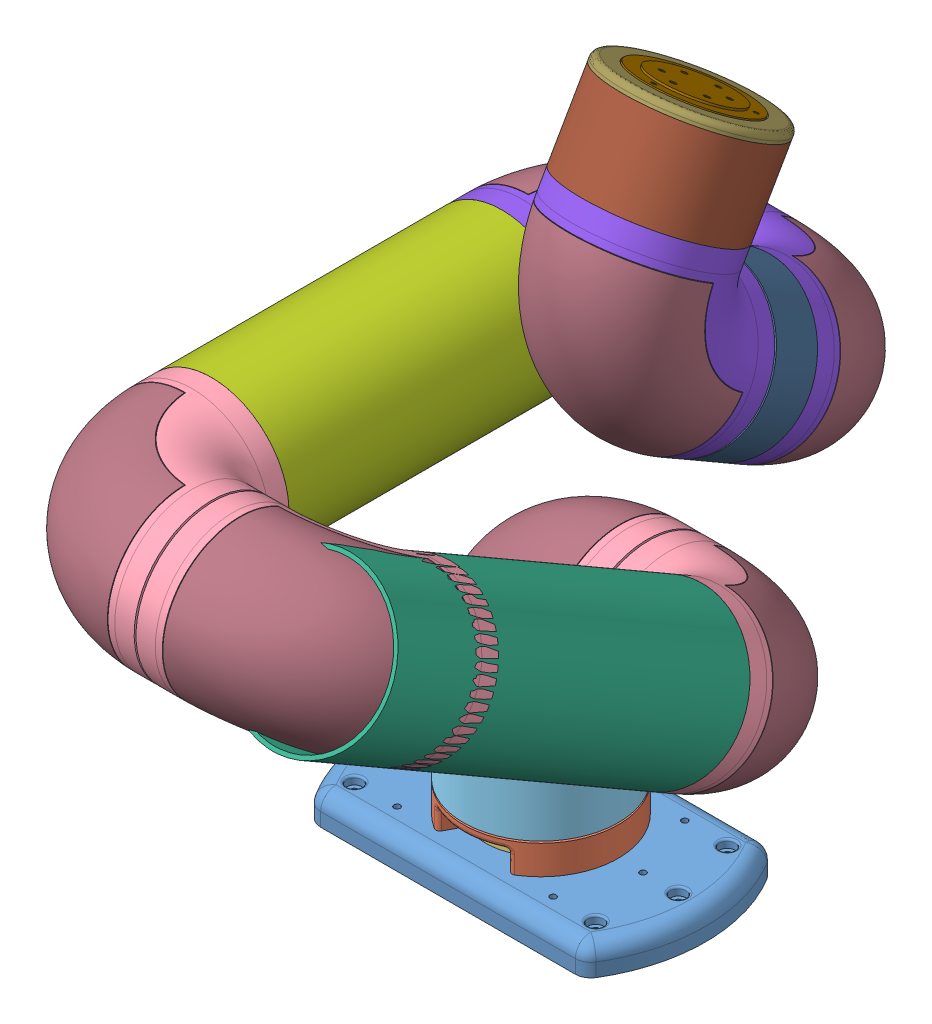
SolidWorks assembly LEG, configuration 默认. Lengths in mm.
Overall size (238.86 430.9 376.17).
28 component instances, 13 part files, 71 mates.
Components (placement in the parent):
- A1-1: A1 [默认] at (-39.3023 -20.665 170) size (170 15 96)
- A2-1: A2 [默认] at (-39.3023 9.335 170) x (0.707107 0 -0.707107) z (-0.707107 0 -0.707107) size (80 15 80)
- 4340_sim-1: 4340_sim [默认] at (-39.3023 63.585 170) x (0 0 1) z (1 0 0) size (57 53.25 57)
- B1-1: B1 [默认] at (-39.3023 49.585 170) size (96.96 109.09 84.56)
- L1-1: L1 [默认] at (-39.3023 10.285 170) size (80 39.3 80)
- 4340_sim-2: 4340_sim [默认] at (-26.4523 104.585 170) x (0 -1 0) z (0 0 1) size (57 53.25 57)
- B1-2: B1 [默认] at (71.6477 132.085 217.6314) x (-1 0 0) z (0 -0.866025 0.5) size (96.96 109.09 84.56)
- L2-1: L2 [默认] at (71.6477 132.085 217.6314) x (1 0 0) z (0 -0.866025 0.5) size (80 210 80)
- B1-3: B1 [默认] at (71.6477 207.085 347.5352) x (-1 0 0) z (0 0.866025 -0.5) size (96.96 109.09 84.56)
- 4340_sim-3: 4340_sim [默认] at (58.7977 234.585 395.1666) x (0 0.866025 -0.5) z (0 0.5 0.866025) size (57 53.25 57)
- B1-4: B1 [默认] at (-39.3023 234.585 340.1666) x (1 0 0) z (0 -1 0) size (96.96 109.09 84.56)
- L3-1: L3 [默认] at (-39.3023 234.585 190.1666) x (1 0 0) z (0 -1 0) size (80 150 80)
- B2-1: B2 [默认] at (-39.3023 234.585 190.1666) x (1 0 0) z (0 1 0) size (96.96 109.09 84.56)
- DM4310_sim-1: DM4310_sim [默认] at (-30.6059 48.3844 133.1666) x (0 0 -1) z (0.993049 -0.117702 0) size (57 61.9 51.54)
- B2-2: B2 [默认] at (71.6977 262.085 182.798) x (-1 0 0) z (0 -0.866025 0.5) size (96.96 109.09 84.56)
- L4-1: L4 [默认] at (71.6977 262.085 182.798) x (1 0 0) z (0 -0.866025 0.5) size (80 24.5 80)
- B2-3: B2 [默认] at (71.6977 349.9664 225.013) x (0 -0.5 -0.866025) z (-1 0 0) size (96.96 109.09 84.56)
- DM4310_sim-2: DM4310_sim [默认] at (73.6977 89.9288 257.0159) x (1 0 0) z (0 0.394592 0.918857) size (57 61.9 51.54)
- L6-1: L6 [默认] at (71.6977 349.9664 225.013) x (1 0 0) z (0 0.5 0.866025) size (80 42 80)
- DM4310_sim-3: DM4310_sim [默认] at (73.6977 424.1843 397.1693) x (1 0 0) z (0 0.918857 -0.394592) size (57 61.9 51.54)
- L7-1: L7 [默认] at (71.6977 386.3395 204.013) x (1 0 0) z (0 0.5 0.866025) size (80 14.5 80)
- C1-1: C1 [默认] at (-39.3023 49.585 170) x (1 0 0) z (0 0 1) size (83.14 83.47 85.73)
- C1-2: C1 [默认] at (71.6477 132.085 217.6314) x (-1 0 0) z (0 -0.866025 0.5) size (83.14 83.47 85.73)
- C1-3: C1 [默认] at (71.6476 207.0848 347.5349) x (-1 0.000004 0.000006) z (0 0.866025 -0.5) size (83.14 83.47 85.73)
- C1-4: C1 [默认] at (-39.3023 234.585 340.1666) x (1 0 0) z (0 -1 0) size (83.14 83.47 85.73)
- C1-5: C1 [默认] at (-39.3023 234.585 190.1666) x (1 0 0) z (0 1 0) size (83.14 83.47 85.73)
- C1-6: C1 [默认] at (71.6977 262.085 182.798) x (-1 0 0) z (0 -0.866025 0.5) size (83.14 83.47 85.73)
- C1-7: C1 [默认] at (71.6977 349.9664 225.013) x (0 -0.5 -0.866025) z (-1 0 0) size (83.14 83.47 85.73)
Mates (geometry in assembly coordinates):
- 重合1: coincident anti-aligned: plane of A1-1 through (-39.3023 -5.665 170) normal (0 1 0); plane of A2-1 through (-39.3023 -5.665 170) normal (0 -1 0)
- 同心1: concentric anti-aligned: cylinder of A1-1 through (-63.6975 -5.665 145.6048) axis (0 -1 0) radius 1.6; cylinder of A2-1 through (-63.6975 -5.665 145.6048) axis (0 1 0) radius 1.6
- 同心2: concentric anti-aligned: cylinder of A1-1 through (-14.9071 -5.665 194.3952) axis (0 -1 0) radius 1.6; cylinder of A2-1 through (-14.9071 -5.665 194.3952) axis (0 1 0) radius 1.6
- 重合2: coincident anti-aligned: plane of A1-1 through (-39.3023 -5.665 170) normal (0 1 0); plane of 4340_sim-1 through (-39.3023 -5.665 170) normal (0 -1 0)
- 同心7: concentric aligned: cylinder of A1-1 through (-39.3023 -5.665 183.5) axis (0 -1 0) radius 1.6; cylinder of 4340_sim-1 through (-39.3023 0.335 183.5) axis (0 -1 0) radius 1.5
- 同心8: concentric aligned: cylinder of A1-1 through (-39.3023 -5.665 156.5) axis (0 -1 0) radius 1.6; cylinder of 4340_sim-1 through (-39.3023 0.335 156.5) axis (0 -1 0) radius 1.5
- 同心9: concentric anti-aligned: cylinder of 4340_sim-1 through (-52.7373 43.585 183.435) axis (0 1 0) radius 1.5; cylinder of B1-1 through (-52.7373 146.673 183.435) axis (0 -1 0) radius 1.6
- 同心10: concentric anti-aligned: cylinder of 4340_sim-1 through (-25.8673 43.585 156.565) axis (0 1 0) radius 1.5; cylinder of B1-1 through (-25.8673 146.673 156.565) axis (0 -1 0) radius 1.6
- 重合3: coincident anti-aligned: plane of 4340_sim-1 through (-39.3023 47.585 170) normal (0 1 0); plane of B1-1 through (-39.3023 47.585 170) normal (0 -1 0)
- 重合4: coincident anti-aligned: plane of B1-1 through (-39.3023 49.585 170) normal (0 -1 0); plane of L1-1 through (-39.3023 49.585 170) normal (0 1 0)
- 同心11: concentric anti-aligned: cylinder of B1-1 through (-39.3023 47.585 170) axis (0 1 0) radius 37.8; cylinder of L1-1 through (-39.3023 49.585 170) axis (0 -1 0) radius 38
- 重合5: coincident anti-aligned: plane of B1-1 through (-10.4523 104.585 170) normal (1 0 0); plane of 4340_sim-2 through (-10.4523 104.585 170) normal (-1 0 0)
- 同心12: concentric anti-aligned: cylinder of B1-1 through (-81.2649 118.02 183.435) axis (1 0 0) radius 1.6; cylinder of 4340_sim-2 through (-6.4523 118.02 183.435) axis (-1 0 0) radius 1.5
- 同心13: concentric anti-aligned: cylinder of B1-1 through (-81.2649 91.15 156.565) axis (1 0 0) radius 1.6; cylinder of 4340_sim-2 through (-6.4523 91.15 156.565) axis (-1 0 0) radius 1.5
- 同心21: concentric anti-aligned: cylinder of 4340_sim-2 through (36.7977 97.835 158.3087) axis (1 0 0) radius 1.5; cylinder of B1-2 through (113.6104 97.835 158.3087) axis (-1 0 0) radius 1.6
- 同心22: concentric anti-aligned: cylinder of 4340_sim-2 through (36.7977 111.335 181.6913) axis (1 0 0) radius 1.5; cylinder of B1-2 through (113.6104 111.335 181.6913) axis (-1 0 0) radius 1.6
- 重合7: coincident anti-aligned: plane of B1-2 through (71.6477 132.085 217.6314) normal (0 0.5 0.866025); plane of L2-1 through (71.6477 132.085 217.6314) normal (0 -0.5 -0.866025)
- 同心23: concentric aligned: cylinder of B1-2 through (71.6477 133.085 219.3634) axis (0 -0.5 -0.866025) radius 37.8; cylinder of L2-1 through (71.6477 207.085 347.5352) axis (0 -0.5 -0.866025) radius 40
- 同心24: concentric anti-aligned: cylinder of L2-1 through (71.6477 207.085 347.5352) axis (0 -0.5 -0.866025) radius 40; cylinder of B1-3 through (71.6477 206.085 345.8032) axis (0 0.5 0.866025) radius 37.8
- 重合8: coincident anti-aligned: plane of L2-1 through (71.6477 207.085 347.5352) normal (0 0.5 0.866025); plane of B1-3 through (71.6477 207.085 347.5352) normal (0 -0.5 -0.866025)
- 重合9: coincident anti-aligned: plane of 4340_sim-2 through (42.7977 104.585 170) normal (1 0 0); plane of B1-2 through (42.7977 104.585 170) normal (-1 0 0)
- 重合10: coincident aligned: plane of B1-2 through (16.6477 104.585 170) normal (-1 0 0); plane of B1-3 through (16.6477 234.585 395.1666) normal (-1 0 0)
- 重合11: coincident anti-aligned: plane of B1-3 through (42.7977 234.585 395.1666) normal (-1 0 0); plane of 4340_sim-3 through (42.7977 234.585 395.1666) normal (1 0 0)
- 同心25: concentric anti-aligned: cylinder of B1-3 through (113.6104 229.6675 413.5192) axis (-1 0 0) radius 1.6; cylinder of 4340_sim-3 through (38.7977 229.6675 413.5192) axis (1 0 0) radius 1.5
- 同心26: concentric anti-aligned: cylinder of B1-3 through (113.6104 239.5026 376.814) axis (-1 0 0) radius 1.6; cylinder of 4340_sim-3 through (38.7977 239.5026 376.814) axis (1 0 0) radius 1.5
- 同心30: concentric anti-aligned: cylinder of 4340_sim-3 through (-4.4523 222.8937 401.9166) axis (-1 0 0) radius 1.5; cylinder of B1-4 through (-81.2649 222.8937 401.9166) axis (1 0 0) radius 1.6
- 同心31: concentric anti-aligned: cylinder of 4340_sim-3 through (-4.4523 246.2764 388.4166) axis (-1 0 0) radius 1.5; cylinder of B1-4 through (-81.2649 246.2764 388.4166) axis (1 0 0) radius 1.6
- 重合12: coincident anti-aligned: plane of 4340_sim-3 through (-10.4523 234.585 395.1666) normal (-1 0 0); plane of B1-4 through (-10.4523 234.585 395.1666) normal (1 0 0)
- 重合13: coincident anti-aligned: plane of B1-4 through (-39.3023 234.585 340.1666) normal (0 0 -1); plane of L3-1 through (-39.3023 234.585 340.1666) normal (0 0 1)
- 同心32: concentric anti-aligned: cylinder of B1-4 through (-39.3023 234.585 338.1666) axis (0 0 1) radius 37.8; cylinder of L3-1 through (-39.3023 234.585 340.1666) axis (0 0 -1) radius 40
- 同心34: concentric aligned: cylinder of L3-1 through (-39.3023 234.585 340.1666) axis (0 0 -1) radius 40; cylinder of B2-1 through (-39.3023 234.585 192.1666) axis (0 0 -1) radius 37.8
- 重合14: coincident anti-aligned: plane of L3-1 through (-39.3023 234.585 190.1666) normal (0 0 -1); plane of B2-1 through (-39.3023 234.585 190.1666) normal (0 0 1)
- 重合15: coincident aligned: plane of B1-4 through (15.6977 234.585 395.1666) normal (1 0 0); plane of B2-1 through (15.6977 234.585 135.1666) normal (1 0 0)
- 重合16: coincident anti-aligned: plane of B2-1 through (-6.8023 234.585 135.1666) normal (1 0 0); plane of DM4310_sim-1 through (-6.8023 234.585 135.1666) normal (-1 0 0)
- 同心35: concentric anti-aligned: cylinder of B2-1 through (-81.2649 248.02 121.7316) axis (1 0 0) radius 1.6; cylinder of DM4310_sim-1 through (-6.8023 248.02 121.7316) axis (-1 0 0) radius 1.025
- 同心36: concentric anti-aligned: cylinder of B2-1 through (-81.2649 221.15 148.6016) axis (1 0 0) radius 1.6; cylinder of DM4310_sim-1 through (-6.8023 221.15 148.6016) axis (-1 0 0) radius 1.025
- 同心37: concentric anti-aligned: cylinder of DM4310_sim-1 through (39.1977 248.085 135.1666) axis (1 0 0) radius 1.25; cylinder of B2-2 through (113.6604 248.085 135.1666) axis (-1 0 0) radius 1.6
- 同心38: concentric anti-aligned: cylinder of DM4310_sim-1 through (39.1977 221.085 135.1666) axis (1 0 0) radius 1.25; cylinder of B2-2 through (113.6604 221.085 135.1666) axis (-1 0 0) radius 1.6
- 重合17: coincident anti-aligned: plane of DM4310_sim-1 through (39.1977 234.585 135.1666) normal (1 0 0); plane of B2-2 through (39.1977 234.585 135.1666) normal (-1 0 0)
- 重合18: coincident anti-aligned: plane of B2-2 through (71.6977 262.085 182.798) normal (0 0.5 0.866025); plane of L4-1 through (71.6977 262.085 182.798) normal (0 -0.5 -0.866025)
- 同心39: concentric aligned: cylinder of B2-2 through (71.6977 263.085 184.5301) axis (0 -0.5 -0.866025) radius 37.8; cylinder of L4-1 through (71.6977 274.335 204.0156) axis (0 -0.5 -0.866025) radius 38
- 重合19: coincident anti-aligned: plane of B2-2 through (71.6977 263.085 184.5301) normal (0 0.5 0.866025); plane of DM4310_sim-2 through (71.6977 263.085 184.5301) normal (0 -0.5 -0.866025)
- 同心40: concentric anti-aligned: cylinder of B2-2 through (58.2627 225.1761 91.9998) axis (0 0.5 0.866025) radius 1.6; cylinder of DM4310_sim-2 through (58.2627 274.7201 177.8125) axis (0 -0.5 -0.866025) radius 1.025
- 同心41: concentric anti-aligned: cylinder of B2-2 through (85.1327 201.906 105.4349) axis (0 0.5 0.866025) radius 1.6; cylinder of DM4310_sim-2 through (85.1327 251.4499 191.2476) axis (0 -0.5 -0.866025) radius 1.025
- 重合21: coincident anti-aligned: plane of B2-3 through (71.6977 286.085 224.3672) normal (0 -0.5 -0.866025); plane of DM4310_sim-2 through (71.6977 286.085 224.3672) normal (0 0.5 0.866025)
- 同心44: concentric anti-aligned: cylinder of B2-3 through (71.6977 335.0077 282.1038) axis (0 -0.5 -0.866025) radius 1.6; cylinder of DM4310_sim-2 through (71.6977 297.7764 217.6172) axis (0 0.5 0.866025) radius 1.25
- 同心45: concentric anti-aligned: cylinder of B2-3 through (71.6977 311.625 295.6038) axis (0 -0.5 -0.866025) radius 1.6; cylinder of DM4310_sim-2 through (71.6977 274.3937 231.1172) axis (0 0.5 0.866025) radius 1.25
- 重合22: coincident anti-aligned: plane of B2-3 through (71.6977 349.9664 225.013) normal (0 0.866025 -0.5); plane of L6-1 through (71.6977 349.9664 225.013) normal (0 -0.866025 0.5)
- 同心46: concentric aligned: cylinder of B2-3 through (71.6977 351.6985 224.013) axis (0 -0.866025 0.5) radius 37.8; cylinder of L6-1 through (71.6977 386.3395 204.013) axis (0 -0.866025 0.5) radius 40
- 重合23: coincident anti-aligned: plane of B2-3 through (71.6977 351.6985 224.013) normal (0 0.866025 -0.5); plane of DM4310_sim-3 through (71.6977 351.6985 224.013) normal (0 -0.866025 0.5)
- 同心48: concentric anti-aligned: cylinder of B2-3 through (58.2627 259.1682 261.922) axis (0 0.866025 -0.5) radius 1.6; cylinder of DM4310_sim-3 through (58.2627 344.9809 212.378) axis (0 -0.866025 0.5) radius 1.025
- 同心49: concentric anti-aligned: cylinder of B2-3 through (85.1327 272.6033 285.1921) axis (0 0.866025 -0.5) radius 1.6; cylinder of DM4310_sim-3 through (85.1327 358.416 235.6481) axis (0 -0.866025 0.5) radius 1.025
- 同心50: concentric anti-aligned: cylinder of L6-1 through (71.6977 386.3395 204.013) axis (0 -0.866025 0.5) radius 38; cylinder of L7-1 through (71.6977 377.6792 209.013) axis (0 0.866025 -0.5) radius 37.8
- 重合24: coincident anti-aligned: plane of L6-1 through (71.6977 386.3395 204.013) normal (0 0.866025 -0.5); plane of L7-1 through (71.6977 386.3395 204.013) normal (0 -0.866025 0.5)
- 同心51: concentric aligned: cylinder of B1-1 through (5.6977 59.585 130) axis (0 0 1) radius 45; cylinder of C1-1 through (5.6977 59.585 130) axis (0 0 1) radius 45.3244
- 相切1: tangent aligned: torus of B1-1 through (5.6977 104.585 170) axis (1 0 0) radius 40; edge_curve of C1-1
- 同心52: concentric aligned: cylinder of B1-2 through (26.6477 161.726 188.9711) axis (0 -0.866025 0.5) radius 45; cylinder of C1-2 through (26.6477 161.726 188.9711) axis (0 -0.866025 0.5) radius 45.3244
- 相切2: tangent aligned: cylinder of B1-2 through (26.6477 104.585 170) axis (-1 0 0) radius 40; edge_curve of C1-2
- 同心53: concentric aligned: cylinder of B1-3 through (26.6477 177.444 376.1955) axis (0 0.866025 -0.5) radius 45; cylinder of C1-3 through (26.6477 177.444 376.1955) axis (0 0.866025 -0.5) radius 45.3244
- 相切4: tangent aligned: cylinder of B1-3 through (26.6477 234.585 395.1666) axis (-1 0 0) radius 40; edge_curve of C1-3
- 同心54: concentric aligned: cylinder of B1-4 through (5.6977 274.585 350.1666) axis (0 -1 0) radius 45; cylinder of C1-4 through (5.6977 274.585 350.1666) axis (0 -1 0) radius 45.3244
- 相切5: tangent aligned: cylinder of B1-4 through (5.6977 234.585 395.1666) axis (1 0 0) radius 40; edge_curve of C1-4
- 同心55: concentric aligned: cylinder of B2-1 through (5.6977 194.585 180.1666) axis (0 1 0) radius 45; cylinder of C1-5 through (5.6977 194.585 180.1666) axis (0 1 0) radius 45.3244
- 相切6: tangent aligned: cylinder of B2-1 through (5.6977 234.585 135.1666) axis (1 0 0) radius 40; edge_curve of C1-5
- 同心56: concentric aligned: cylinder of B2-2 through (26.6977 291.726 154.1377) axis (0 -0.866025 0.5) radius 45; cylinder of C1-6 through (26.6977 291.726 154.1377) axis (0 -0.866025 0.5) radius 45.3244
- 相切7: tangent aligned: cylinder of B2-2 through (71.6977 262.085 182.798) axis (0 -0.5 -0.866025) radius 40; edge_curve of C1-6
- 同心57: concentric aligned: cylinder of B2-3 through (111.6977 318.8062 191.0419) axis (-1 0 0) radius 45; cylinder of C1-7 through (111.6977 318.8062 191.0419) axis (-1 0 0) radius 45.3244
- 相切8: tangent aligned: cylinder of B2-3 through (71.6977 349.9664 225.013) axis (0 -0.866025 0.5) radius 40; edge_curve of C1-7
- 重合25: coincident anti-aligned: plane of L2-1 through (71.6477 207.085 347.5352) normal (0 0.5 0.866025); plane of B1-3 through (71.6477 207.085 347.5352) normal (0 -0.5 -0.866025)
- 平行1: parallel anti-aligned: plane of B1-4 through (2.1622 274.585 435.093) normal (-1 0 0); plane of C1-4 through (1.8408 274.585 395.3266) normal (1 0 0)
- 平行2: parallel anti-aligned: plane of B2-3 through (111.6977 247.0255 236.567) normal (0 0.5 0.866025); plane of C1-7 through (111.6977 281.6249 216.9621) normal (0 -0.5 -0.866025)
